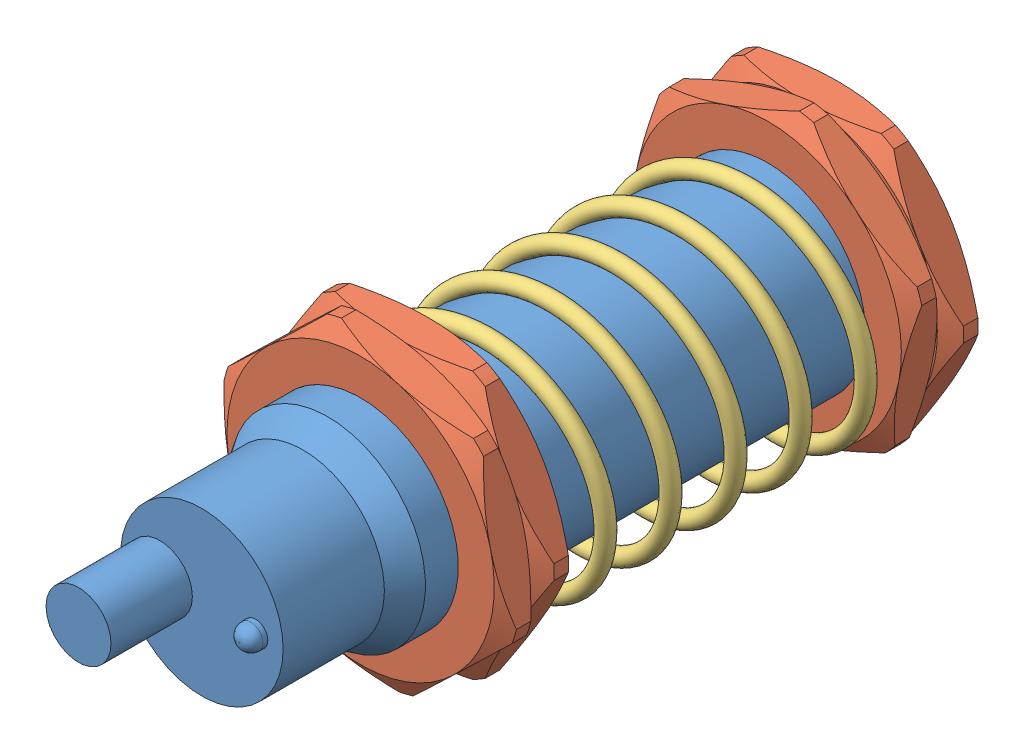
SolidWorks assembly door proximity sensore all, configuration Default. Lengths in mm.
Overall size (24.71 24.65 44.97).
6 component instances, 3 part files, 8 mates.
Components (placement in the parent):
- proximity sensor body-1: proximity sensor body [Default] at (7.1956 22.2405 40.4109) size (12.33 12.33 44.97)
- proximity sensor nut-1: proximity sensor nut [Défaut] at (13.1956 22.2405 30.8711) x (0 0 -1) z (-0.946946 -0.321392 0) size (2.07 16.43 18.47)
- proximity sensor nut-2: proximity sensor nut [Défaut] at (13.1956 22.2405 18.8287) x (0 0 1) z (0.721529 0.692384 0) size (2.07 16.43 18.47)
- proximity sensor spring-1: proximity sensor spring [Default] at (7.1956 22.2405 13.3711) x (1 0 0) z (0 -1 0) size (15 21 17.32)
- proximity sensor nut-3: proximity sensor nut [Défaut] at (13.1956 22.2405 28.6579) x (0 0 -1) z (0.999978 0.006648 0) size (2.07 16.43 18.47)
- proximity sensor nut-4: proximity sensor nut [Défaut] at (13.1956 22.2405 16.7617) x (0 0 1) z (-1 0 0) size (2.07 16.43 18.47)
Mates (geometry in assembly coordinates):
- Concentric1: concentric aligned: cylinder of proximity sensor body-1 through (13.1956 22.2405 48.1594) axis (0 0 1) radius 6; cylinder of proximity sensor nut-2 through (13.1956 22.2405 37.3622) axis (0 0 1) radius 5.0528
- Concentric2: concentric anti-aligned: cylinder of proximity sensor body-1 through (13.1956 22.2405 48.1594) axis (0 0 1) radius 6; cylinder of proximity sensor nut-1 through (13.1956 22.2405 12.3376) axis (0 0 -1) radius 5.0528
- Coincident2: coincident aligned: plane of proximity sensor spring-1; plane of proximity sensor body-1 through (7.1956 22.2405 40.4109) normal (1 0 0)
- Coincident5: coincident anti-aligned: plane of proximity sensor body-1 through (7.1956 22.2405 40.4109) normal (0 1 0); plane of proximity sensor spring-1 through (7.1956 22.2405 13.3711) normal (0 -1 0)
- Coincident6: coincident aligned: plane of proximity sensor nut-1 through (13.1956 22.2405 13.3711) normal (0 0 1); plane of proximity sensor spring-1 through (7.1956 22.2405 13.3711) normal (0 0 1)
- Concentric4: concentric anti-aligned: cylinder of proximity sensor body-1 through (13.1956 22.2405 48.1594) axis (0 0 1) radius 6; cylinder of proximity sensor nut-3 through (13.1956 22.2405 10.1244) axis (0 0 -1) radius 5.0528
- Coincident7: coincident anti-aligned: plane of proximity sensor nut-2 through (13.1956 22.2405 36.3287) normal (0 0 -1); plane of proximity sensor nut-4 through (13.1956 22.2405 36.3287) normal (0 0 1)
- Concentric5: concentric aligned: cylinder of proximity sensor body-1 through (13.1956 22.2405 48.1594) axis (0 0 1) radius 6; cylinder of proximity sensor nut-4 through (13.1956 22.2405 35.2952) axis (0 0 1) radius 5.0528
